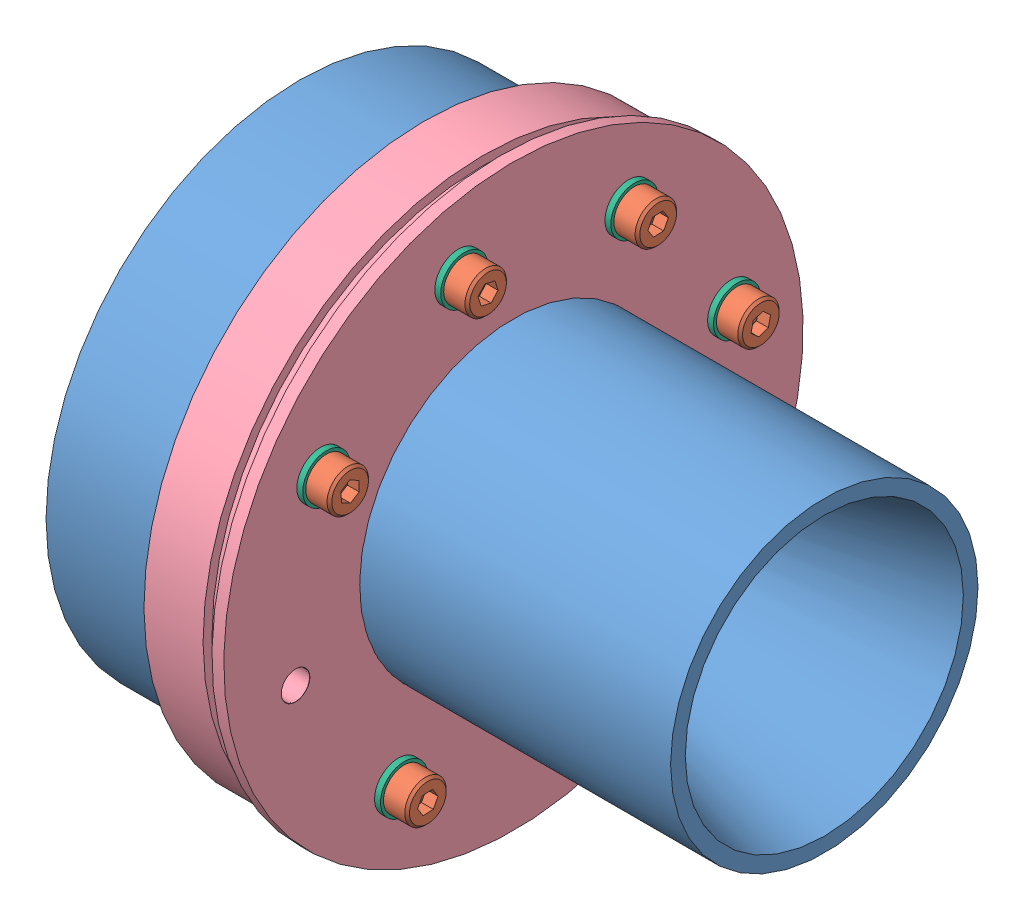
SolidWorks assembly Nozzle graphite O-ring free, configuration Standard. Lengths in mm.
Overall size (88.78 119.78 119.39).
23 component instances, 6 part files, 13 mates.
Components (placement in the parent):
- Nozzle-1: Nozzle [Standard] at origin size (88.78 85.72 85.72)
- CB4-15.stp-1: CB4-15.stp [Standard] at (17.2 19.4813 32.6264) x (-1 0 0) z (0 0.885843 -0.463985) size (19 7 7) (hidden)
- Nozzle clamp-1: Nozzle clamp [Standard] at (2 0 0) x (0 -0.802208 -0.597044) z (0 -0.597044 0.802208) size (42.8 4 42.8)
- Nozzle retainer-1: Nozzle retainer [Standard] at (16.2 0 0) x (1 0 0) z (0 -0.244605 0.969623) size (15 98 98)
- Seal nozzle-1: Seal nozzle [Standard] at (11 0 0) x (0 0 -1) z (1 0 0) size (56 56 1)
- Seal bolt-1: Seal bolt [Standard] at (17.2 19.4813 32.6264) x (0 0 1) z (-1 0 0) size (8 8 1) (hidden)
- Seal bolt-2: Seal bolt [Standard] at (17.2 -9.295 36.8457) x (0 -0.707107 0.707107) z (-1 0 0) size (8 8 1) (hidden)
- Seal bolt-3: Seal bolt [Standard] at (17.2 -32.6264 19.4813) x (0 -1 0) z (-1 0 0) size (8 8 1)
- Seal bolt-4: Seal bolt [Standard] at (17.2 -36.8457 -9.295) x (0 -0.707107 -0.707107) z (-1 0 0) size (8 8 1)
- Seal bolt-5: Seal bolt [Standard] at (17.2 -19.4813 -32.6264) x (0 0 -1) z (-1 0 0) size (8 8 1)
- Seal bolt-6: Seal bolt [Standard] at (17.2 9.295 -36.8457) x (0 0.707107 -0.707107) z (-1 0 0) size (8 8 1)
- Seal bolt-7: Seal bolt [Standard] at (17.2 32.6264 -19.4813) x (0 1 0) z (-1 0 0) size (8 8 1)
- Seal bolt-8: Seal bolt [Standard] at (17.2 36.8457 9.295) x (0 0.707107 0.707107) z (-1 0 0) size (8 8 1)
- CB4-15.stp-2: CB4-15.stp [Standard] at (17.2 -9.295 36.8457) x (-1 0 0) z (0 0.954472 0.298299) size (19 7 7) (hidden)
- CB4-15.stp-3: CB4-15.stp [Standard] at (17.2 -32.6264 19.4813) x (-1 0 0) z (0 0.463985 0.885843) size (19 7 7)
- CB4-15.stp-4: CB4-15.stp [Standard] at (17.2 -36.8457 -9.295) x (-1 0 0) z (0 -0.298299 0.954472) size (19 7 7)
- CB4-15.stp-5: CB4-15.stp [Standard] at (17.2 -19.4813 -32.6264) x (-1 0 0) z (0 -0.885843 0.463985) size (19 7 7)
- CB4-15.stp-6: CB4-15.stp [Standard] at (17.2 9.295 -36.8457) x (-1 0 0) z (0 -0.954472 -0.298299) size (19 7 7)
- CB4-15.stp-7: CB4-15.stp [Standard] at (17.2 32.6264 -19.4813) x (-1 0 0) z (0 -0.463985 -0.885843) size (19 7 7)
- CB4-15.stp-8: CB4-15.stp [Standard] at (17.2 36.8457 9.295) x (-1 0 0) z (0 0.298299 -0.954472) size (19 7 7)
- Nozzle clamp-2: Nozzle clamp [Standard] at (2 0 0) x (0 0.597044 -0.802208) z (0 -0.802208 -0.597044) size (42.8 4 42.8) (hidden)
- Nozzle clamp-3: Nozzle clamp [Standard] at (2 0 0) x (0 0.802208 0.597044) z (0 0.597044 -0.802208) size (42.8 4 42.8)
- Nozzle clamp-4: Nozzle clamp [Standard] at (2 0 0) x (0 -0.597044 0.802208) z (0 0.802208 0.597044) size (42.8 4 42.8)
Mates (geometry in assembly coordinates):
- Concentric1: concentric anti-aligned: cylinder of Nozzle-1 through (0 0 0) axis (1 0 0) radius 26; cylinder of Seal nozzle-1 through (12 0 0) axis (-1 0 0) radius 28
- Coincident1: coincident anti-aligned: plane of Nozzle-1 through (11 26 0) normal (1 0 0); plane of Seal nozzle-1 through (11 0 0) normal (-1 0 0)
- Coincident2: coincident aligned: plane of Nozzle-1 through (0 33 0) normal (1 0 0)
- Concentric2: concentric: cylinder of Nozzle-1 through (0 0 0) axis (1 0 0) radius 26
- Concentric3: concentric aligned: cylinder of Nozzle-1 through (0 0 0) axis (1 0 0) radius 26; cylinder of Nozzle retainer-1 through (16.2 0 0) axis (1 0 0) radius 26
- Coincident4: coincident anti-aligned: plane of Nozzle retainer-1 through (12 0 0) normal (-1 0 0); plane of Seal nozzle-1 through (12 0 0) normal (1 0 0)
- Concentric4: concentric anti-aligned: cylinder of Nozzle-1 through (0 0 0) axis (1 0 0) radius 26; cylinder of Nozzle clamp-1 through (6 0 0) axis (-1 0 0) radius 33
- Coincident5: coincident anti-aligned: plane of Nozzle-1 through (6 35 0) normal (-1 0 0); plane of Nozzle clamp-1 through (6 0 0) normal (1 0 0)
- Concentric5: concentric aligned: cylinder of Nozzle clamp-1 through (6 36.8457 9.295) axis (1 0 0) radius 1.65; cylinder of Nozzle retainer-1 through (16.2 36.8457 9.295) axis (1 0 0) radius 2.4
- Concentric6: concentric anti-aligned: cylinder of CB4-15.stp-1 through (2.2 19.4813 32.6264) axis (-1 0 0) radius 2; cylinder of Nozzle retainer-1 through (16.2 19.4813 32.6264) axis (1 0 0) radius 2.4
- Concentric7: concentric anti-aligned: cylinder of CB4-15.stp-1 through (2.2 19.4813 32.6264) axis (-1 0 0) radius 2; cylinder of Seal bolt-1 through (16.2 19.4813 32.6264) axis (1 0 0) radius 4
- Coincident6: coincident anti-aligned: plane of CB4-15.stp-1 through (17.2 21.1052 35.7268) normal (-1 0 0); plane of Seal bolt-1 through (17.2 19.4813 32.6264) normal (1 0 0)
- Coincident7: coincident anti-aligned: plane of Nozzle retainer-1 through (16.2 47.5115 11.9857) normal (1 0 0); plane of Seal bolt-1 through (16.2 19.4813 32.6264) normal (-1 0 0)
